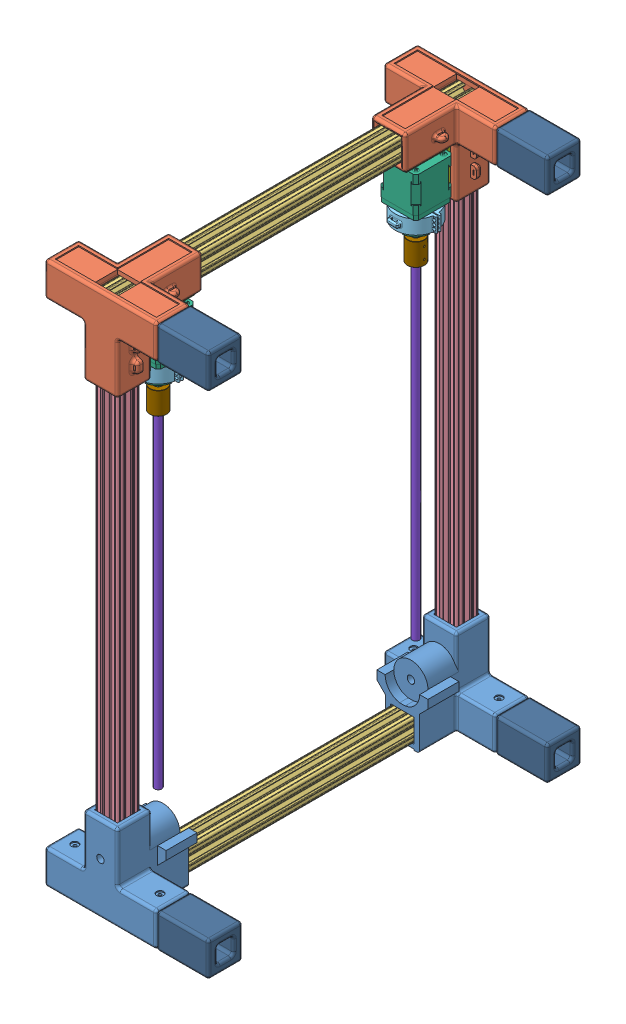
SolidWorks assembly MANDELBOT3PT3, configuration Default. Lengths in mm.
Overall size (183.1 628.84 416.75).
26 component instances, 10 part files, 62 mates.
Components (placement in the parent):
- 3-bottom_leftnright_courner-1: 3-bottom_leftnright_courner [Default] at (-233.6715 -850.4146 -39.4134) x (1 0 0) z (0 0 -1) size (124.9 95.25 79.43)
- 3-bottom_leftnright_courner-2: 3-bottom_leftnright_courner [Default] at (-233.6715 -850.4146 -456.1639) x (-1 0 0) z (0 0 1) size (124.9 95.25 79.43)
- 3-Top_leftnright_courner-1: 3-Top_leftnright_courner [Default] at (-233.6715 -282.0896 -456.1639) size (124.9 134.97 141.56)
- 3-1010-1: 3-1010 [Default] at (-233.6715 -850.4146 -45.3824) x (-1 0 0) z (0 0 1) size (25.4 25.4 404.81)
- 3-1010 - Copy-1: 3-1010 - Copy [Default] at (-233.6715 -294.7896 -437.1139) x (-1 0 0) z (0 1 0) size (25.4 25.4 542.92)
- 3-1010-2: 3-1010 [Default] at (-233.6715 -282.0896 -450.1949) x (-1 0 0) z (0 0 -1) size (25.4 25.4 404.81)
- 3-1010 - Copy-2: 3-1010 - Copy [Default] at (-233.6715 -294.7896 -58.4634) x (-1 0 0) z (0 1 0) size (25.4 25.4 542.92)
- 3-Top_leftnright_courner-2: 3-Top_leftnright_courner [Default] at (-233.6715 -282.0896 -39.4134) x (-1 0 0) z (0 0 -1) size (124.9 134.97 141.56)
- 3-StepperandClamp-1: 3-StepperandClamp [Default] at (-169.3666 -349.3049 -231.1482) x (0.019579 0 -0.999808) z (-0.999808 0 -0.019579) size (53.34 87.3 49.25)
  - 3-SteppermotormountNew-1: 3-SteppermotormountNew [Default] at (-128.5327 11.5427 61.6662) size (53.34 15.88 49.25)
  - 3-Nema17SW-1: 3-Nema17SW [Default] at (-128.5327 -2.8313 61.6662) x (0.999808 0 0.019579) z (0 1 0) size (42.88 42 87.3)
- 3-Eraser-1: 3-Eraser [Default] at (-233.6715 -282.0896 -82.8474) size (25.4 51.18 6.6)
- 3-Eraser-2: 3-Eraser [Default] at (-233.6715 -306.4736 -58.4634) x (-1 0 0) z (0 1 0) size (25.4 51.18 6.6)
- 3-FakeLeadscrew-1: 3-FakeLeadscrew [Default] at (-233.5376 -774.7736 -103.8474) x (0.569946 0 0.821682) z (0 1 0) size (8 8 381)
- 3-Eraser-3: 3-Eraser [Default] at (-233.6715 -306.4736 -341.8639) x (-1 0 0) z (0 1 0) size (25.4 51.18 6.6)
- 3-Eraser-4: 3-Eraser [Default] at (-233.6715 -282.0896 -412.7299) x (-1 0 0) z (0 0 -1) size (25.4 51.18 6.6)
- 3-StepperandClamp-2: 3-StepperandClamp [Default] at (-169.3666 -349.3049 -519.0307) x (0.019579 0 -0.999808) z (-0.999808 0 -0.019579) size (53.34 87.3 49.25)
  - 3-SteppermotormountNew-1: 3-SteppermotormountNew [Default] at (-128.5327 11.5427 61.6662) size (53.34 15.88 49.25)
  - 3-Nema17SW-1: 3-Nema17SW [Default] at (-128.5327 -2.8313 61.6662) x (0.999808 0 0.019579) z (0 1 0) size (42.88 42 87.3)
- 3-FakeLeadscrew-3: 3-FakeLeadscrew [Default] at (-233.5376 -774.7736 -391.7299) x (0.569946 0 0.821682) z (0 1 0) size (8 8 381)
- 3-Y-leadscrew_colles-1: 3-Y-leadscrew_colles [Default] at (-233.5376 -409.6636 -391.7299) size (18.9 25 18.9)
- 3-Y-leadscrew_colles-2: 3-Y-leadscrew_colles [Default] at (-233.5376 -409.6636 -103.8474) x (0.605381 0 -0.795936) z (0.795936 0 0.605381) size (18.9 25 18.9)
- 3-endExtender-1: 3-endExtender [Default] at (-214.6215 -850.4146 -58.4634) x (0 0 -1) z (0 -1 0) size (38.1 101.6 38.1)
- 3-endExtender-2: 3-endExtender [Default] at (-214.6215 -282.0896 -58.4634) x (0 -1 0) z (0 0 1) size (38.1 101.6 38.1)
- 3-endExtender-3: 3-endExtender [Default] at (-214.6215 -282.0896 -437.1139) x (0 -1 0) z (0 0 1) size (38.1 101.6 38.1)
- 3-endExtender-4: 3-endExtender [Default] at (-214.6215 -850.4146 -437.1139) x (0 -1 0) z (0 0 1) size (38.1 101.6 38.1)
Mates (geometry in assembly coordinates):
- Distance5: distance = 0 mm: plane of assembly; plane of assembly; plane of 3-Top_leftnright_courner-1 through (-233.6715 -257.8326 -450.1949) normal (0 0 1); plane of 3-1010-2 through (-231.9623 -289.7604 -450.1949) normal (0 0 -1)
- Distance6: distance = 0.381 mm: plane of assembly; plane of assembly; plane of 3-Top_leftnright_courner-1 through (-220.5905 -269.0086 -360.9139) normal (0 -1 0); plane of 3-1010-2 through (-243.222 -269.3896 -45.3824) normal (0 1 0)
- Distance9: distance = 0.381 mm: plane of assembly; plane of assembly; plane of 3-1010-2 through (-220.9715 -275.7565 -45.3824) normal (1 0 0); plane of 3-Top_leftnright_courner-1 through (-220.5905 -295.1706 -360.9139) normal (-1 0 0)
- Distance10: distance = 0.381 mm: plane of assembly; plane of assembly; plane of 3-1010-1 through (-220.9715 -856.7477 -450.1949) normal (1 0 0); plane of 3-bottom_leftnright_courner-2 through (-220.5905 -837.3336 -360.9139) normal (-1 0 0)
- Distance11: distance = 0.381 mm: plane of assembly; plane of assembly; plane of 3-1010-1 through (-224.1211 -863.1146 -450.1949) normal (0 -1 0); plane of 3-bottom_leftnright_courner-2 through (-246.7525 -863.4956 -360.9139) normal (0 1 0)
- Coincident12: coincident: plane of assembly; plane of assembly; plane of 3-bottom_leftnright_courner-2 through (-233.6715 -874.6716 -450.1949) normal (0 0 1); plane of 3-1010-1 through (-231.9623 -842.7438 -450.1949) normal (0 0 -1)
- Coincident13: coincident: plane of assembly; plane of assembly; plane of 3-bottom_leftnright_courner-1 through (-233.6715 -874.6716 -45.3824) normal (0 0 -1); plane of 3-1010-1 through (-231.9623 -842.7438 -45.3824) normal (0 0 1)
- Distance12: distance = 0.381 mm: plane of assembly; plane of assembly; plane of 3-1010-1 through (-246.3715 -856.7477 -450.1949) normal (-1 0 0); plane of 3-bottom_leftnright_courner-1 through (-246.7525 -837.3336 -134.6634) normal (1 0 0)
- Distance13: distance = 0.381 mm: plane of assembly; plane of assembly; plane of 3-1010-1 through (-243.222 -863.1146 -450.1949) normal (0 -1 0); plane of 3-bottom_leftnright_courner-1 through (-220.5905 -863.4956 -134.6634) normal (0 1 0)
- Coincident16: coincident: plane of assembly; plane of assembly; plane of 3-1010 - Copy-1 through (-231.9623 -294.7896 -444.7847) normal (0 1 0); plane of 3-1010-2 through (-227.3384 -294.7896 -45.3824) normal (0 -1 0)
- Coincident19: coincident: plane of assembly; plane of assembly; plane of 3-1010-2 through (-240.0046 -294.7896 -45.3824) normal (0 -1 0); plane of 3-1010 - Copy-2 through (-231.9623 -294.7896 -66.1342) normal (0 1 0)
- Distance18: distance = 0.381 mm: plane of assembly; plane of assembly; plane of 3-bottom_leftnright_courner-1 through (-246.7525 -837.3336 -134.6634) normal (1 0 0); plane of 3-1010 - Copy-2 through (-246.3715 -837.7146 -52.1304) normal (-1 0 0)
- Distance19: distance = 0.381 mm: plane of assembly; plane of assembly; plane of 3-1010 - Copy-2 through (-224.1211 -837.7146 -45.7634) normal (0 0 1); plane of 3-bottom_leftnright_courner-1 through (-233.6715 -874.6716 -45.3824) normal (0 0 -1)
- Coincident25: coincident: plane of assembly; plane of assembly; plane of 3-1010-1 through (-240.0046 -837.7146 -450.1949) normal (0 1 0); plane of 3-1010 - Copy-2 through (-231.9623 -837.7146 -66.1342) normal (0 -1 0)
- Distance46: distance = 0.381 mm: plane of assembly; plane of assembly; plane of 3-1010 - Copy-2 through (-243.222 -837.7146 -45.7634) normal (0 0 1); plane of 3-Top_leftnright_courner-2 through (-233.6715 -257.8326 -45.3824) normal (0 0 -1)
- Distance47: distance = 0.381 mm: plane of assembly; plane of assembly; plane of 3-1010 - Copy-2 through (-246.3715 -837.7146 -68.0138) normal (-1 0 0); plane of 3-Top_leftnright_courner-2 through (-246.7525 -295.1706 -134.6634) normal (1 0 0)
- Distance55: distance = 0.381 mm: plane of assembly; plane of assembly; plane of 3-1010 - Copy-2 through (-231.9623 -294.7896 -66.1342) normal (0 1 0); plane of 3-Top_leftnright_courner-2 through (-246.7525 -295.1706 -134.6634) normal (0 1 0)
- Distance53: distance = 0.381 mm: plane of assembly; plane of assembly; plane of 3-1010-2 through (-246.3715 -275.7565 -45.3824) normal (-1 0 0); plane of 3-Top_leftnright_courner-2 through (-246.7525 -295.1706 -134.6634) normal (1 0 0)
- Coincident51: coincident: plane of assembly; plane of assembly; plane of 3-1010-2 through (-231.9623 -289.7604 -45.3824) normal (0 0 1); plane of 3-Top_leftnright_courner-2 through (-233.6715 -257.8326 -45.3824) normal (0 0 -1)
- Coincident73: coincident: plane of assembly; plane of assembly; plane of 3-Top_leftnright_courner-2 through (-233.6715 -282.0896 -76.2434) normal (0 0 -1); plane of 3-Eraser-1 through (-233.6715 -282.0896 -76.2434) normal (0 0 1)
- Coincident74: coincident: plane of assembly; plane of assembly; plane of 3-Top_leftnright_courner-2 through (-246.3715 -355.3051 -76.2434) normal (1 0 0); plane of 3-Eraser-1 through (-246.3715 -355.3051 -76.2434) normal (-1 0 0)
- Coincident76: coincident: plane of assembly; line of assembly; plane of 3-Eraser-2 through (-246.3715 -299.8696 -80.4979) normal (0 0 1); line of 3-Top_leftnright_courner-2 through (-220.9715 -301.1396 -80.4979) axis (-1 0 0)
- Coincident77: coincident: plane of assembly; plane of assembly; plane of 3-Top_leftnright_courner-2 through (-233.6715 -299.8696 -39.4134) normal (0 -1 0); plane of 3-Eraser-2 through (-233.6715 -299.8696 -58.4634) normal (0 1 0)
- Coincident78: coincident: plane of assembly; plane of assembly; plane of 3-Top_leftnright_courner-2 through (-220.9715 -309.0136 -80.4979) normal (-1 0 0); plane of 3-Eraser-2 through (-220.9715 -299.8696 -131.6789) normal (1 0 0)
- Coincident79: coincident: plane of assembly; plane of assembly; plane of 3-StepperandClamp-1/3-Nema17SW-1 through (-233.5376 -306.4736 -103.8474) normal (0 1 0); plane of 3-Eraser-2 through (-233.6715 -306.4736 -58.4634) normal (0 -1 0)
- Coincident80: coincident: plane of assembly; plane of assembly; plane of 3-StepperandClamp-1/3-Nema17SW-1 through (-212.5376 -306.4736 -82.8474) normal (0 0 1); plane of 3-Eraser-1 through (-233.6715 -282.0896 -82.8474) normal (0 0 -1)
- Concentric3: concentric: cylinder of assembly; cylinder of assembly; cylinder of 3-StepperandClamp-1/3-Nema17SW-1 through (-233.5376 -393.7736 -103.8474) axis (0 1 0) radius 4; cylinder of 3-FakeLeadscrew-1 through (-233.5376 -393.7736 -103.8474) axis (0 -1 0) radius 4
- Coincident90: coincident: plane of assembly; plane of assembly; plane of 3-StepperandClamp-1/3-Nema17SW-1 through (-233.5376 -393.7736 -103.8474) normal (0 -1 0); plane of 3-FakeLeadscrew-1 through (-233.5376 -393.7736 -103.8474) normal (0 1 0)
- Coincident136: coincident: plane of assembly; plane of assembly; plane of 3-Top_leftnright_courner-1 through (-233.6715 -299.8696 -456.1639) normal (0 -1 0); plane of 3-Eraser-3 through (-233.6715 -299.8696 -341.8639) normal (0 1 0)
- Coincident137: coincident: plane of assembly; plane of assembly; plane of 3-Top_leftnright_courner-1 through (-246.3715 -309.0136 -415.0794) normal (0 0 1); plane of 3-Eraser-3 through (-220.9715 -299.8696 -415.0794) normal (0 0 -1)
- Coincident138: coincident: plane of assembly; plane of assembly; plane of 3-Top_leftnright_courner-1 through (-246.3715 -309.0136 -415.0794) normal (1 0 0); plane of 3-Eraser-3 through (-246.3715 -299.8696 -415.0794) normal (-1 0 0)
- Coincident139: coincident: plane of assembly; plane of assembly; plane of 3-Top_leftnright_courner-1 through (-233.6715 -282.0896 -419.3339) normal (0 0 1); plane of 3-Eraser-4 through (-233.6715 -282.0896 -419.3339) normal (0 0 -1)
- Coincident140: coincident: plane of assembly; plane of assembly; plane of 3-Top_leftnright_courner-1 through (-246.3715 -355.3051 -419.3339) normal (1 0 0); plane of 3-Eraser-4 through (-246.3715 -355.3051 -419.3339) normal (-1 0 0)
- Coincident141: coincident: plane of assembly; plane of assembly; plane of 3-Top_leftnright_courner-1 through (-220.9715 -304.1241 -419.3339) normal (0 -1 0); plane of 3-Eraser-4 through (-246.3715 -304.1241 -419.3339) normal (0 1 0)
- Coincident143: coincident: plane of assembly; plane of assembly; plane of 3-Eraser-4 through (-233.6715 -282.0896 -412.7299) normal (0 0 1); plane of 3-StepperandClamp-2/3-Nema17SW-1 through (-254.5376 -306.4736 -412.7299) normal (0 0 -1)
- Coincident144: coincident: plane of assembly; plane of assembly; plane of 3-StepperandClamp-1/3-Nema17SW-1 through (-254.5376 -306.4736 -82.8474) normal (-1 0 0); plane of 3-StepperandClamp-2/3-Nema17SW-1 through (-254.5376 -306.4736 -370.7299) normal (-1 0 0)
- Coincident145: coincident: plane of assembly; plane of assembly; plane of 3-StepperandClamp-1/3-SteppermotormountNew-1 through (-233.5376 -368.7852 -103.8474) normal (0 -1 0); plane of 3-StepperandClamp-2/3-SteppermotormountNew-1 through (-233.5376 -368.7852 -391.7299) normal (0 -1 0)
- Coincident146: coincident: plane of assembly; plane of assembly; plane of 3-StepperandClamp-2/3-Nema17SW-1 through (-233.5376 -393.7736 -391.7299) normal (0 -1 0); plane of 3-FakeLeadscrew-3 through (-233.5376 -393.7736 -391.7299) normal (0 1 0)
- Concentric27: concentric: cylinder of assembly; cylinder of assembly; cylinder of 3-StepperandClamp-2/3-Nema17SW-1 through (-233.5376 -393.7736 -391.7299) axis (0 1 0) radius 4; cylinder of 3-FakeLeadscrew-3 through (-233.5376 -393.7736 -391.7299) axis (0 -1 0) radius 4
- Distance88: distance = 2.0839 mm: plane of assembly; plane of assembly; plane of 3-StepperandClamp-1/3-Nema17SW-1 through (-212.5376 -306.4736 -124.8474) normal (1 0 0); plane of 3-Top_leftnright_courner-2 through (-214.6215 -301.1396 -134.6634) normal (1 0 0)
- Concentric54: concentric: cylinder of assembly; cylinder of assembly; cylinder of 3-FakeLeadscrew-1 through (-233.5376 -393.7736 -103.8474) axis (0 -1 0) radius 4; cylinder of 3-Y-leadscrew_colles-2 through (-233.5376 -384.6636 -103.8474) axis (0 -1 0) radius 4
- Concentric55: concentric: cylinder of assembly; cylinder of assembly; cylinder of 3-FakeLeadscrew-3 through (-233.5376 -393.7736 -391.7299) axis (0 -1 0) radius 4; cylinder of 3-Y-leadscrew_colles-1 through (-233.5376 -384.6636 -391.7299) axis (0 -1 0) radius 4
- Coincident234: coincident: plane of assembly; plane of assembly; plane of 3-Y-leadscrew_colles-1 through (-233.5376 -384.6636 -391.7299) normal (0 1 0); plane of 3-Y-leadscrew_colles-2 through (-233.5376 -384.6636 -103.8474) normal (0 1 0)
- Distance122: distance = 8.89 mm: plane of assembly; plane of assembly; plane of 3-Y-leadscrew_colles-2 through (-233.5376 -384.6636 -103.8474) normal (0 1 0); plane of 3-StepperandClamp-1/3-Nema17SW-1 through (-233.5376 -375.7736 -103.8474) normal (0 -1 0)
- Width4: width: plane of assembly; plane of assembly; plane of assembly; plane of assembly; plane of 3-endExtender-1 through (-113.0215 -837.5241 -58.4634) normal (0 1 0); plane of 3-endExtender-1 through (-113.0215 -863.3051 -58.4634) normal (0 -1 0); plane of 3-bottom_leftnright_courner-1 through (-206.7475 -837.3336 -39.4134) normal (0 -1 0); plane of 3-bottom_leftnright_courner-1 through (-206.7475 -863.4956 -39.4134) normal (0 1 0)
- Parallel55: parallel: plane of assembly; plane of assembly; plane of 3-bottom_leftnright_courner-1 through (-296.1215 -850.4146 -77.5134) normal (0 0 -1); plane of 3-endExtender-1 through (-113.0215 -850.4146 -71.3539) normal (0 0 -1)
- Width5: width: plane of assembly; plane of assembly; plane of assembly; plane of assembly; plane of 3-endExtender-1 through (-113.0215 -850.4146 -71.3539) normal (0 0 -1); plane of 3-endExtender-1 through (-113.0215 -850.4146 -45.5729) normal (0 0 1); plane of 3-bottom_leftnright_courner-1 through (-233.6715 -874.6716 -45.3824) normal (0 0 -1); plane of 3-bottom_leftnright_courner-1 through (-206.7475 -850.4146 -71.5444) normal (0 0 1)
- Coincident275: coincident: plane of assembly; plane of assembly; plane of 3-bottom_leftnright_courner-1 through (-214.6215 -850.4146 -39.4134) normal (1 0 0); plane of 3-endExtender-1 through (-214.6215 -850.4146 -58.4634) normal (-1 0 0)
- Width8: width: plane of assembly; plane of assembly; plane of assembly; plane of assembly; plane of 3-endExtender-2 through (-113.0215 -282.0896 -45.5729) normal (0 0 1); plane of 3-endExtender-2 through (-113.0215 -282.0896 -71.3539) normal (0 0 -1); plane of 3-Top_leftnright_courner-2 through (-171.2215 -282.0896 -71.5444) normal (0 0 1); plane of 3-Top_leftnright_courner-2 through (-233.6715 -257.8326 -45.3824) normal (0 0 -1)
- Parallel56: parallel: plane of assembly; plane of assembly; plane of 3-Top_leftnright_courner-2 through (-171.2215 -301.1396 -39.4134) normal (0 -1 0); plane of 3-endExtender-2 through (-59.14 -301.1396 -58.4634) normal (0 -1 0)
- Width9: width: plane of assembly; plane of assembly; plane of assembly; plane of assembly; plane of 3-endExtender-2 through (-113.0215 -269.1991 -58.4634) normal (0 1 0); plane of 3-endExtender-2 through (-113.0215 -294.9801 -58.4634) normal (0 -1 0); plane of 3-Top_leftnright_courner-2 through (-171.2215 -269.0086 -39.4134) normal (0 -1 0); plane of 3-Top_leftnright_courner-2 through (-171.2215 -295.1706 -39.4134) normal (0 1 0)
- Coincident276: coincident: plane of assembly; plane of assembly; plane of 3-Top_leftnright_courner-2 through (-214.6215 -282.0896 -39.4134) normal (1 0 0); plane of 3-endExtender-2 through (-214.6215 -282.0896 -58.4634) normal (-1 0 0)
- Width10: width: plane of assembly; plane of assembly; plane of assembly; plane of assembly; plane of 3-endExtender-3 through (-113.0215 -269.1991 -437.1139) normal (0 1 0); plane of 3-endExtender-3 through (-113.0215 -294.9801 -437.1139) normal (0 -1 0); plane of 3-Top_leftnright_courner-1 through (-206.7475 -269.0086 -456.1639) normal (0 -1 0); plane of 3-Top_leftnright_courner-1 through (-206.7475 -295.1706 -456.1639) normal (0 1 0)
- Width11: width: plane of assembly; plane of assembly; plane of assembly; plane of assembly; plane of 3-endExtender-3 through (-113.0215 -282.0896 -450.0044) normal (0 0 -1); plane of 3-endExtender-3 through (-113.0215 -282.0896 -424.2234) normal (0 0 1); plane of 3-Top_leftnright_courner-1 through (-206.7475 -282.0896 -424.0329) normal (0 0 -1); plane of 3-Top_leftnright_courner-1 through (-233.6715 -257.8326 -450.1949) normal (0 0 1)
- Coincident277: coincident: plane of assembly; plane of assembly; plane of 3-Top_leftnright_courner-1 through (-214.6215 -282.0896 -456.1639) normal (1 0 0); plane of 3-endExtender-3 through (-214.6215 -282.0896 -437.1139) normal (-1 0 0)
- Width12: width: plane of assembly; plane of assembly; plane of assembly; plane of assembly; plane of 3-endExtender-4 through (-113.0215 -850.4146 -450.0044) normal (0 0 -1); plane of 3-endExtender-4 through (-113.0215 -850.4146 -424.2234) normal (0 0 1); plane of 3-bottom_leftnright_courner-2 through (-171.2215 -850.4146 -424.0329) normal (0 0 -1); plane of 3-bottom_leftnright_courner-2 through (-233.6715 -874.6716 -450.1949) normal (0 0 1)
- Parallel57: parallel: plane of assembly; plane of assembly; plane of 3-bottom_leftnright_courner-2 through (-171.2215 -863.4956 -456.1639) normal (0 1 0); plane of 3-endExtender-4 through (-113.0215 -863.3051 -437.1139) normal (0 -1 0)
- Width13: width: plane of assembly; plane of assembly; plane of assembly; plane of assembly; plane of 3-endExtender-4 through (-113.0215 -837.5241 -437.1139) normal (0 1 0); plane of 3-endExtender-4 through (-113.0215 -863.3051 -437.1139) normal (0 -1 0); plane of 3-bottom_leftnright_courner-2 through (-171.2215 -837.3336 -456.1639) normal (0 -1 0); plane of 3-bottom_leftnright_courner-2 through (-171.2215 -863.4956 -456.1639) normal (0 1 0)
- Coincident279: coincident: plane of assembly; plane of assembly; plane of 3-bottom_leftnright_courner-2 through (-214.6215 -850.4146 -456.1639) normal (1 0 0); plane of 3-endExtender-4 through (-214.6215 -850.4146 -437.1139) normal (-1 0 0)
- Coincident281: coincident: plane of assembly; plane of assembly; plane of 3-Top_leftnright_courner-2 through (-246.3715 -304.1241 -76.2434) normal (0 -1 0); plane of 3-Eraser-1 through (-220.9715 -304.1241 -76.2434) normal (0 1 0)
- Width17: width: plane of assembly; plane of assembly; plane of assembly; plane of assembly; plane of 3-1010 - Copy-1 through (-243.222 -837.7146 -424.4139) normal (0 0 1); plane of 3-1010 - Copy-1 through (-240.0046 -837.7146 -449.8139) normal (0 0 -1); plane of 3-Top_leftnright_courner-1 through (-233.6715 -355.1146 -449.8952) normal (0 0 1); plane of 3-Top_leftnright_courner-1 through (-233.6715 -355.1146 -424.3327) normal (0 0 -1)
- Width18: width: plane of assembly; plane of assembly; plane of assembly; plane of assembly; plane of 3-1010 - Copy-1 through (-246.3715 -837.7146 -430.7809) normal (-1 0 0); plane of 3-1010 - Copy-1 through (-220.9715 -837.7146 -430.7809) normal (1 0 0); plane of 3-Top_leftnright_courner-1 through (-220.8902 -355.1146 -456.1639) normal (-1 0 0); plane of 3-Top_leftnright_courner-1 through (-246.4528 -355.1146 -456.1639) normal (1 0 0)
